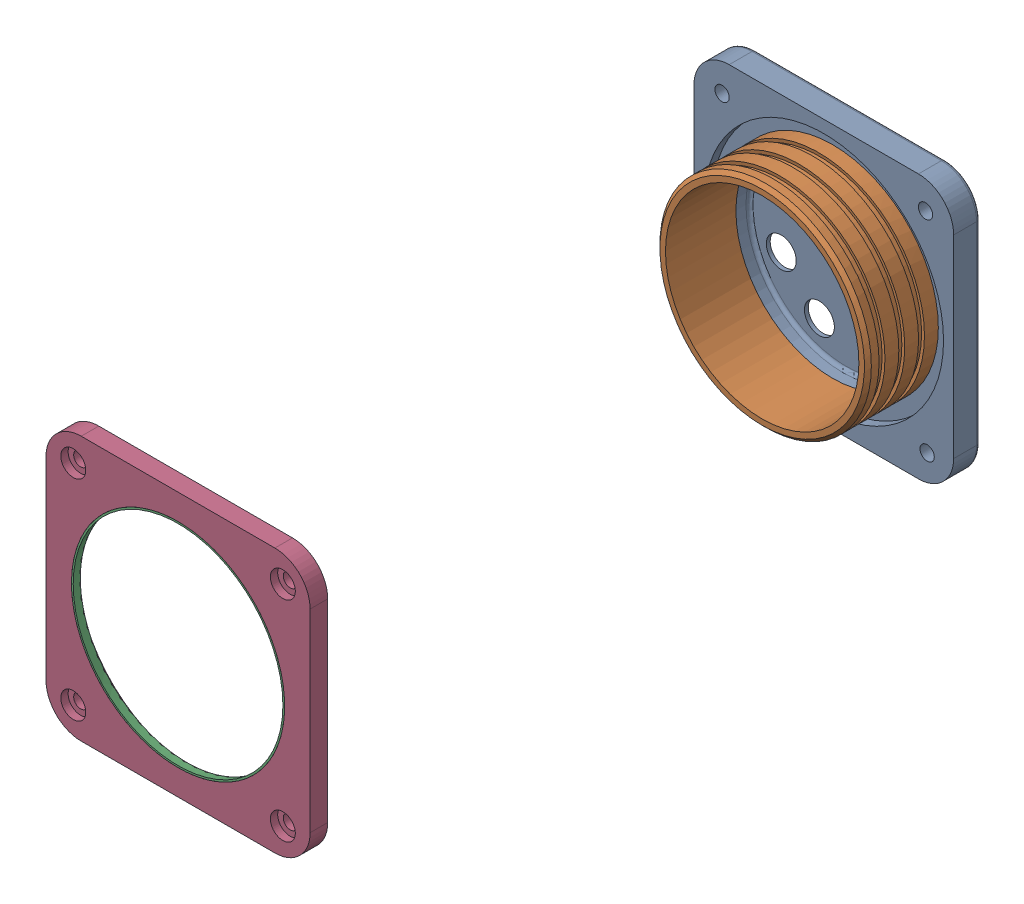
SolidWorks assembly Rear Endcap, configuration Default. Lengths in mm.
Overall size (190.5 190.5 484.84).
3 component instances, 3 part files, 2 mates.
Components (placement in the parent):
- Rear Endcap Outer-1: Rear Endcap Outer [Default] at origin size (187.32 190.5 19.05)
- Rear Endcap Inner-1: Rear Endcap Inner [Default] at (0 0 63.5) x (1 0 0) z (0 1 0) size (152.5 50.8 152.5)
- Front_cap (1)-1: Front_cap (1) [Default] at (0 0 484.8352) x (-1 0 0) z (0 0 -1) size (190.5 190.5 12.7)
Mates (geometry in assembly coordinates):
- Coincident1: coincident anti-aligned: plane of Rear Endcap Outer-1 through (0 0 12.7) normal (0 0 1); plane of Rear Endcap Inner-1 through (0 0 12.7) normal (0 0 -1)
- Concentric1: concentric anti-aligned: circle of Rear Endcap Outer-1; circle of Rear Endcap Inner-1
